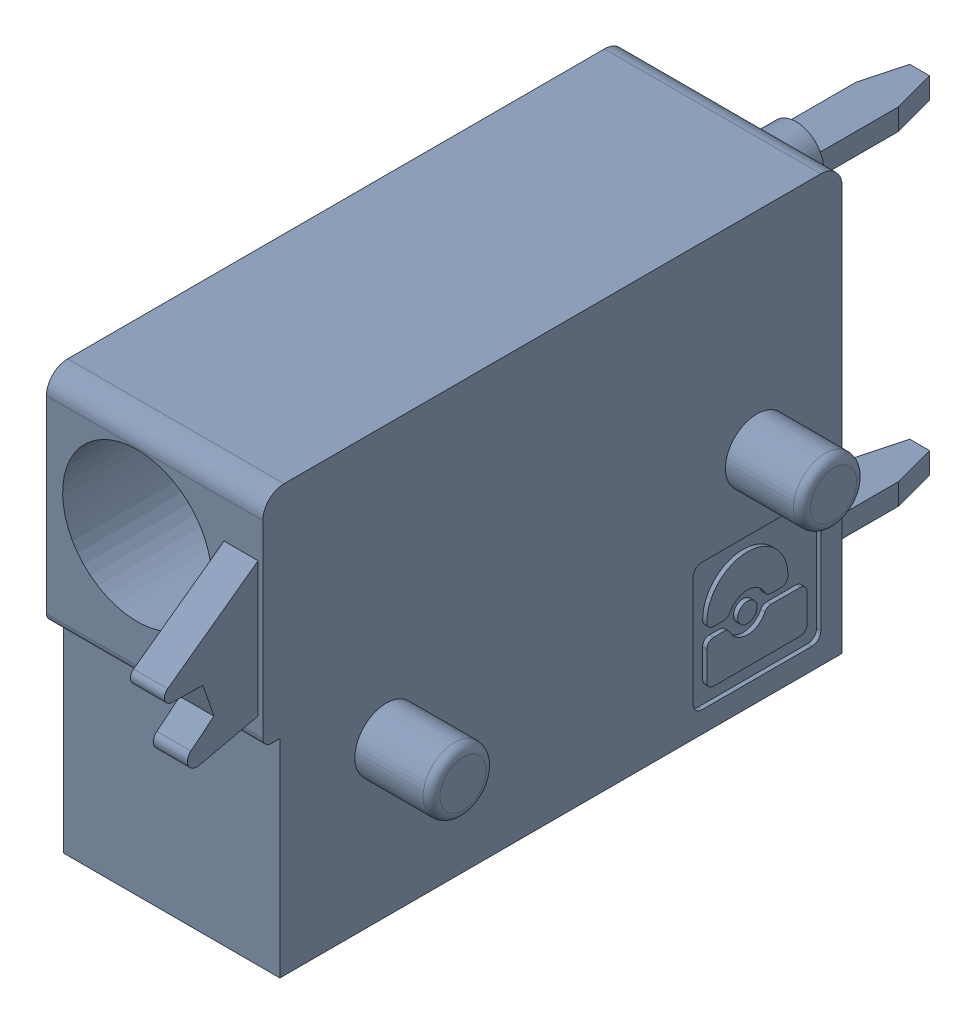
SolidWorks assembly J20, configuration Default. Lengths in mm.
Overall size (6.88 10 19.2).
2 component instances, 1 part files, 0 mates.
Components (placement in the parent):
- 1790348-1: 1790348 [Default] at (45.0851 -7.6199 0) x (0 1 0) z (1 0 0) size (10 19.2 6.88)
  - ffkds-v2-5.08-1: ffkds-v2-5.08 [Default] at (-23.7414 -38.158 -2.54) x (0 -1 0) z (0 0 1) size (19.2 10 6.88)
